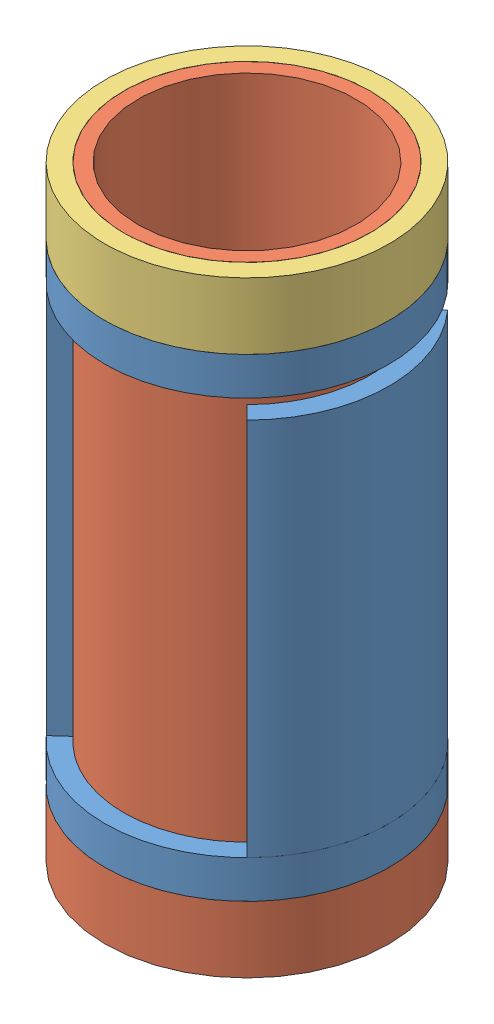
SolidWorks assembly AldermanGrantASSY, configuration Default. Lengths in mm.
Overall size (15 32 15).
3 component instances, 3 part files, 7 mates.
Components (placement in the parent):
- AldermanGrantCoil-2: AldermanGrantCoil [Default] at (1.5149 22.1386 12.6077) size (15 25 15)
- CoilFormer-4: CoilFormer [Default] at (1.5149 20.1386 12.6077) size (15 32 15)
- CoilFormerTop-1: CoilFormerTop [Default] at (1.5149 45.1386 12.6077) size (15 3.5 15)
Mates (geometry in assembly coordinates):
- Coincident3: coincident anti-aligned: plane of 20170802_AldermanGrantCoil-2 through (1.5149 20.1386 12.6077) normal (0 -1 0); plane of CoilFormer-4 through (1.5149 20.1386 12.6077) normal (0 1 0)
- Coincident4: coincident anti-aligned: plane of CoilFormer-4 through (1.5149 16.6386 12.6077) normal (0 -1 0); plane of ? through (1.5149 16.6386 12.6077) normal (0 1 0)
- Concentric4: concentric anti-aligned: circle of CoilFormer-4; circle of ?
- Coincident5: coincident: plane of CoilFormer-4 through (1.5149 48.6386 12.6077) normal (0 1 0); plane of ? through (7.6514 48.6386 12.2009) normal (0 -1 0)
- Concentric6: concentric: circle of CoilFormer-4; circle of ?
- Coincident6: coincident anti-aligned: plane of 20170802_AldermanGrantCoil-2 through (1.5149 45.1386 12.6077) normal (0 1 0); plane of 20170802_CoilFormerTop-1 through (1.5149 45.1386 12.6077) normal (0 -1 0)
- Concentric7: concentric aligned: circle of 20170802_AldermanGrantCoil-2; circle of 20170802_CoilFormerTop-1
